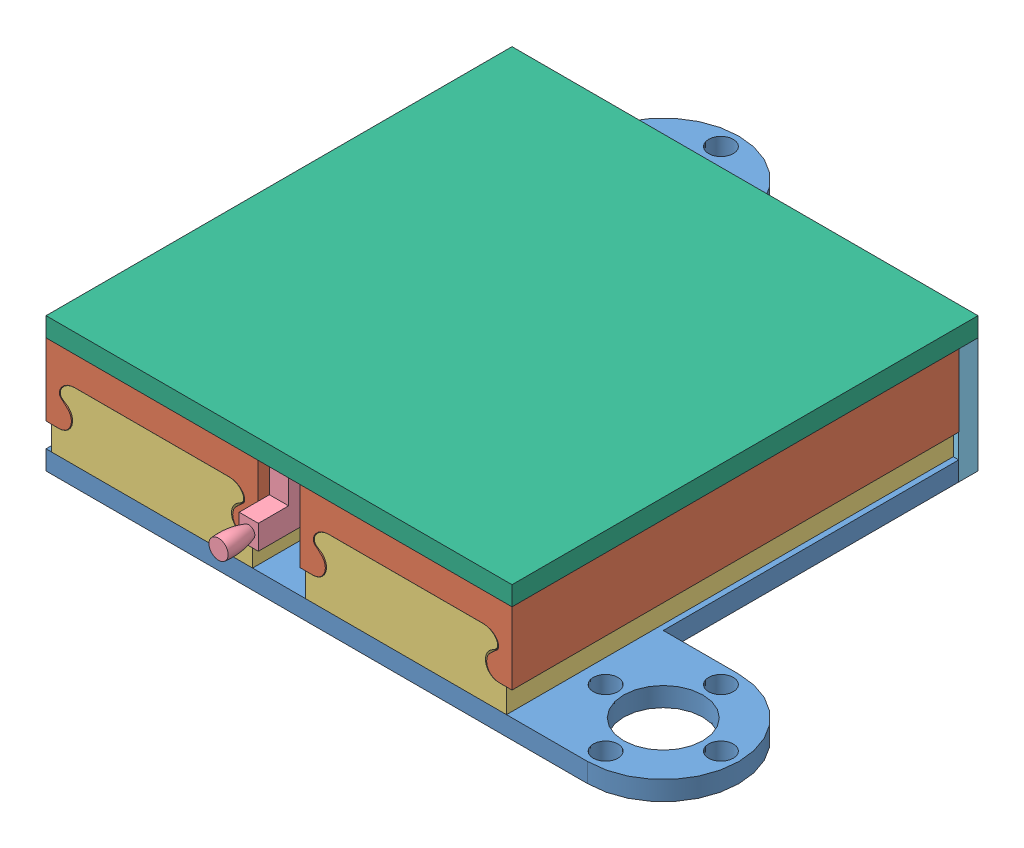
SolidWorks assembly Elevator and Bottom Plate Assembly, configuration Default. Lengths in mm.
Overall size (102 22.22 112).
8 component instances, 6 part files, 21 mates.
Components (placement in the parent):
- Elevator Platform-1: Elevator Platform [Default] at (42.3916 56.1213 78.8759) size (102 3.17 102)
- Slider Outside Piece-1: Slider Outside Piece [Default] at (21.4104 75.1713 117.369) x (0 0 -1) z (-1 0 0) size (73.82 11.91 35.04)
- Slider Outside Piece-2: Slider Outside Piece [Default] at (63.3729 75.1713 117.369) x (0 0 -1) z (-1 0 0) size (73.82 11.91 35.04)
- Slider Inside Piece-1: Slider Inside Piece [Default] at (21.4104 75.1713 117.3759) x (0 0 -1) z (-1 0 0) size (73.82 11.11 33.23)
- Slider Inside Piece-2: Slider Inside Piece [Default] at (63.3729 75.1713 117.3759) x (0 0 -1) z (-1 0 0) size (73.82 11.11 33.23)
- Pulling Knob-1: Pulling Knob [Default] at (41.6081 73.0235 117.369) size (3.45 8 20.01)
- Back Wall-1: Back Wall [Default] at (3.8916 59.2963 41.3989) size (77 19.05 3.18)
- Elevator Slide-3: Elevator Slide [Default] at (42.3916 75.1713 78.869) size (77 3.17 77)
Mates (geometry in assembly coordinates):
- Parallel1: parallel anti-aligned: plane of Slider Outside Piece-1 through (21.4104 70.4088 43.544) normal (0 -1 0); plane of Slider Inside Piece-1 through (21.4104 70.4088 43.5509) normal (0 1 0)
- Parallel2: parallel aligned: plane of Slider Outside Piece-1 through (21.4104 75.1713 117.369) normal (0 0 1); plane of Slider Inside Piece-1 through (21.4104 75.1713 117.3759) normal (0 0 1)
- Parallel3: parallel anti-aligned: plane of Slider Outside Piece-1 through (21.4104 63.265 43.544) normal (0 -1 0); plane of Slider Inside Piece-1 through (21.4104 63.265 43.5509) normal (0 1 0)
- Coincident16: coincident anti-aligned: plane of Slider Outside Piece-1 through (21.4104 70.4088 43.544) normal (0 -1 0); plane of Slider Inside Piece-1 through (21.4104 70.4088 43.5509) normal (0 1 0)
- Coincident17: coincident aligned: line of Slider Outside Piece-1 through (6.0645 63.265 43.544) axis (0 0 1); line of Slider Inside Piece-1 through (6.0645 63.265 43.5509) axis (0 0 1)
- Parallel4: parallel anti-aligned: plane of Slider Outside Piece-2 through (63.3729 70.4088 43.544) normal (0 -1 0); plane of Slider Inside Piece-2 through (63.3729 70.4088 43.5509) normal (0 1 0)
- Parallel5: parallel aligned: plane of Slider Outside Piece-2 through (63.3729 75.1713 43.544) normal (0 0 -1); plane of Slider Inside Piece-2 through (63.3729 75.1713 43.5509) normal (0 0 -1)
- Coincident20: coincident aligned: line of Slider Outside Piece-2 through (78.7187 63.265 43.544) axis (0 0 1); line of Slider Inside Piece-2 through (78.7187 63.265 43.5509) axis (0 0 1)
- Coincident24: coincident anti-aligned: plane of Elevator Platform-1 through (42.3916 59.2963 78.8759) normal (0 1 0); plane of Slider Inside Piece-1 through (21.4104 59.2963 43.5509) normal (0 -1 0)
- Coincident25: coincident anti-aligned: plane of Elevator Platform-1 through (42.3916 59.2963 78.8759) normal (0 1 0); plane of Slider Inside Piece-2 through (63.3729 59.2963 43.5509) normal (0 -1 0)
- Coincident28: coincident aligned: plane of Elevator Platform-1 through (42.3916 59.2963 117.3759) normal (0 0 1); plane of Slider Inside Piece-1 through (21.4104 75.1713 117.3759) normal (0 0 1)
- Coincident41: coincident anti-aligned: plane of Elevator Platform-1 through (42.3916 59.2963 78.8759) normal (0 1 0); plane of Back Wall-1 through (80.8916 59.2963 43.5509) normal (0 -1 0)
- Coincident42: coincident anti-aligned: line of Elevator Platform-1 through (28.8916 59.2963 40.3759) axis (1 0 0); line of Back Wall-1 through (10.8916 59.2963 40.3759) axis (-1 0 0)
- Coincident45: coincident anti-aligned: plane of Slider Outside Piece-2 through (63.3729 75.1713 43.544) normal (0 1 0); plane of Elevator Slide-3 through (42.3916 75.1713 78.869) normal (0 -1 0)
- Coincident46: coincident anti-aligned: plane of Slider Outside Piece-1 through (21.4104 75.1713 43.544) normal (0 1 0); plane of Elevator Slide-3 through (42.3916 75.1713 78.869) normal (0 -1 0)
- Coincident47: coincident aligned: line of Slider Outside Piece-1 through (3.8916 75.1713 117.369) axis (1 0 0); line of Elevator Slide-3 through (3.8916 75.1713 117.369) axis (1 0 0)
- Coincident48: coincident aligned: line of Slider Outside Piece-2 through (45.8541 75.1713 117.369) axis (1 0 0); line of Elevator Slide-3 through (3.8916 75.1713 117.369) axis (1 0 0)
- Coincident49: coincident aligned: line of Slider Outside Piece-2 through (80.8916 75.1713 117.369) axis (0 0 -1); line of Elevator Slide-3 through (80.8916 75.1713 117.369) axis (0 0 -1)
- Coincident50: coincident anti-aligned: plane of Pulling Knob-1 through (40.8041 75.1713 107.369) normal (0 1 0); plane of Elevator Slide-3 through (42.3916 75.1713 78.869) normal (0 -1 0)
- Coincident51: coincident aligned: plane of Pulling Knob-1 through (41.6081 73.0235 117.369) normal (0 0 1); plane of Elevator Slide-3 through (3.8916 78.3463 117.369) normal (0 0 1)
- Coincident52: coincident: point of Pulling Knob-1; unknown of Elevator Slide-3
